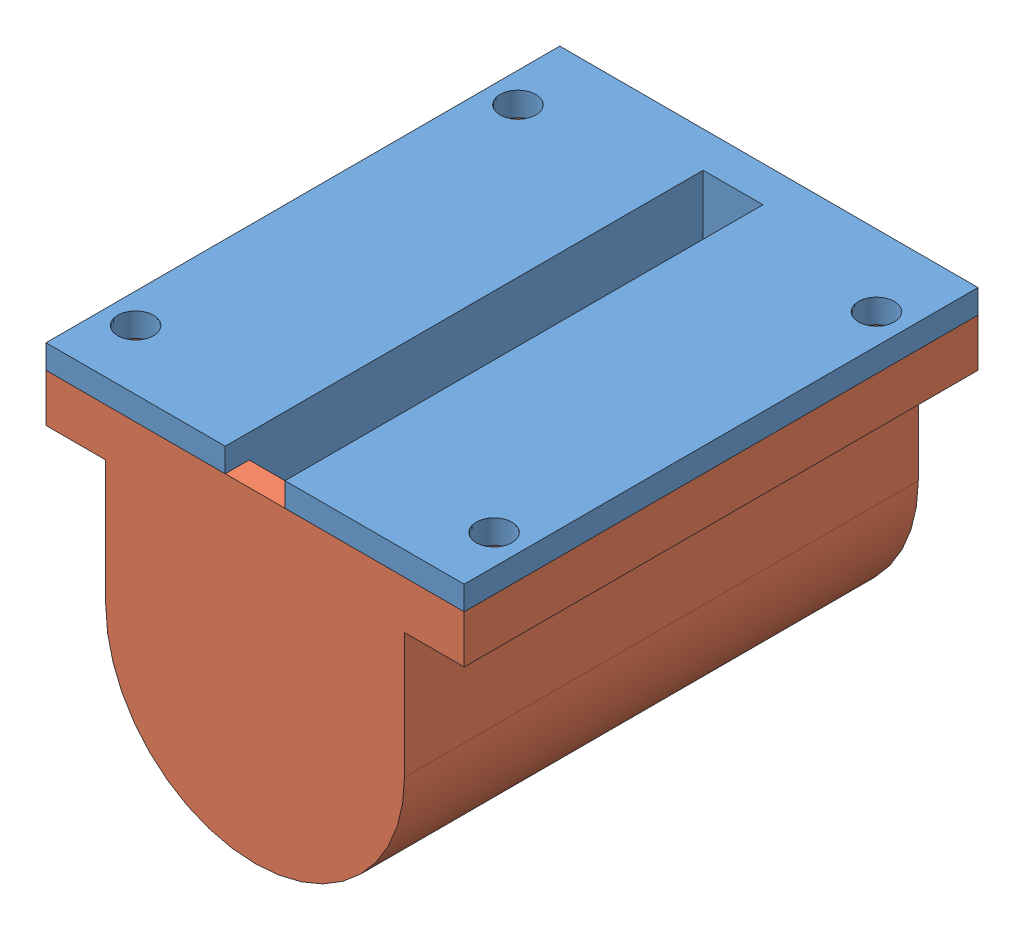
SolidWorks assembly Caja potenciometro, configuration Predeterminado. Lengths in mm.
Overall size (35 29 43).
2 component instances, 2 part files, 3 mates.
Components (placement in the parent):
- tapa inferior potenciometro-2: tapa inferior potenciometro [Predeterminado] at (2.2755 17.5349 -59.2727) size (35 17 43)
- tapa superior potenciometro-2: tapa superior potenciometro [Predeterminado] at (2.2755 18.0349 -21.2727) x (-1 0 0) z (0 0 -1) size (35 27 43)
Mates (geometry in assembly coordinates):
- Coincidente12: coincident anti-aligned: plane of tapa inferior potenciometro-2 through (2.2755 32.5349 -59.2727) normal (0 -1 0); plane of tapa superior potenciometro-2 through (2.2755 32.5349 -21.2727) normal (0 1 0)
- Coincidente13: coincident aligned: plane of tapa inferior potenciometro-2 through (4.7755 32.5349 -59.2727) normal (0 0 1); plane of tapa superior potenciometro-2 through (2.2755 18.0349 -59.2727) normal (0 0 1)
- Coincidente14: coincident: plane of tapa inferior potenciometro-2 through (-15.2245 32.5349 -19.2727) normal (-1 0 0); line of tapa superior potenciometro-2 through (-15.2245 28.5349 -62.2727) axis (0 0 1)
